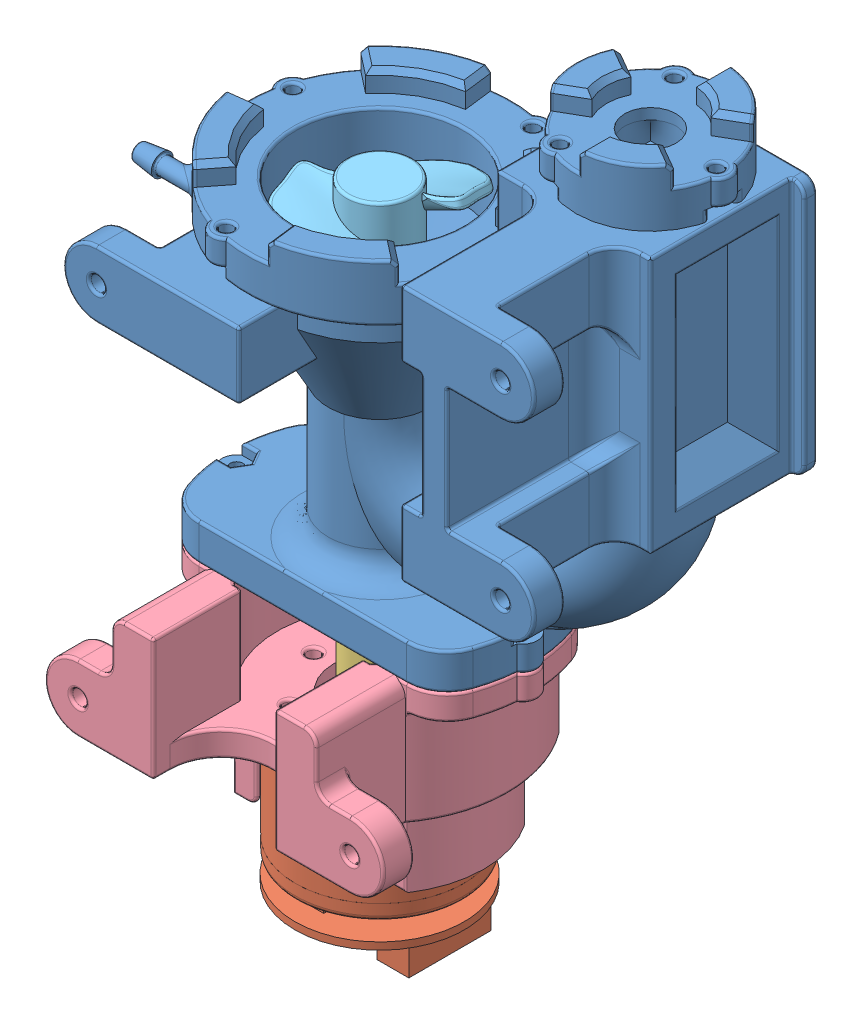
SolidWorks assembly Motor Connector Reference Assembly, configuration Default. Lengths in mm.
Overall size (95.4 152.33 58.74).
6 component instances, 6 part files, 18 mates.
Components (placement in the parent):
- Water Tunnel-1: Water Tunnel [Default] at origin size (93.6 95.16 58.74)
- 10kMotor-1: 10kMotor [Default] at (-41.4 -82.8 26.4) x (0 0 1) z (0 1 0) size (33 33 42.2)
- Shaft Cupling 2 to 3-1: Shaft Cupling 2 to 3 [Default] at (-41.4 -70 26.4) x (0 0 1) z (0 1 0) size (12 12 20)
- Motor Interface-1: Motor Interface [Default] at (0 -59 0) x (-1 0 0) z (0 -1 0) size (66 51.39 41.92)
- 5000rpm10cmHead-1: 5000rpm10cmHead [Default] at (-41.4 2.484 26.4) x (0 0 -1) z (-1 0 0) size (33.19 12.79 25.21)
- ImpellerShaft-1: ImpellerShaft [Default] at (-41.4 -70 26.4) x (0 0 1) z (0 1 0) size (3 3 74)
Mates (geometry in assembly coordinates):
- Coincident1: coordinate: point of Water Tunnel-1
- InPlace1: in place: plane of Water Tunnel-1 through (-41.4 -59 26.4) normal (0 -1 0); plane of Motor Interface-1 through (0 -59 0) normal (0 -1 0); moOrthogonalPlaneRef_w of Water Tunnel-1 through (-41.4 -59 26.4) normal (0 -1 0); plane of Motor Interface-1 through (0 -59 0) normal (0 0 -1); plane of Water Tunnel-1 through (-41.4 -59 26.4) normal (0 -1 0); plane of Motor Interface-1 through (0 -59 0) normal (-1 0 0); plane of Water Tunnel-1 through (-41.4 -59 26.4) normal (0 -1 0); unknown of Motor Interface-1
- Coincident2: coincident aligned: plane of Water Tunnel-1; plane of Motor Interface-1
- Coincident3: coincident aligned: moOrthogonalPlaneRef_w of Water Tunnel-1 through (0 -59 0) normal (0 0 -1); plane of Motor Interface-1 through (0 -59 0) normal (0 0 -1)
- Coincident4: coincident anti-aligned: moOrthogonalPlaneRef_w of Water Tunnel-1 through (0 -59 0) normal (1 0 0); plane of Motor Interface-1 through (0 -59 0) normal (-1 0 0)
- Concentric1: concentric aligned: cylinder of 10kMotor-1 through (-41.4 -114.8 26.4) axis (0 1 0) radius 1; cylinder of Shaft Cupling 2 to 3-1 through (-41.4 -80 26.4) axis (0 1 0) radius 1
- Distance5: distance = 1 mm anti-aligned: plane of 10kMotor-1 through (-41.4 -81 26.4) normal (0 1 0); plane of Shaft Cupling 2 to 3-1 through (-41.4 -80 26.4) normal (0 -1 0)
- Concentric2: concentric aligned: cylinder of 10kMotor-1 through (-41.4 -102.2 26.4) axis (0 1 0) radius 16.4; cylinder of Water Tunnel-1 through (-41.4 -59 26.4) axis (0 1 0) radius 5
- Distance3: distance = 1 mm anti-aligned: plane of Shaft Cupling 2 to 3-1 through (-41.4 -60 26.4) normal (0 1 0); plane of Water Tunnel-1 through (-41.4 -59 26.4) normal (0 -1 0)
- Parallel1: parallel anti-aligned: plane of Water Tunnel-1 through (0 0 0) normal (0 0 -1); plane of 10kMotor-1 through (-27.7 -115.5 34.4) normal (0 0 1)
- Coincident2: coincident aligned: plane of Water Tunnel-1 through (0 9 0) normal (0 1 0); plane of 5000rpm10cmHead-1 through (-41.4 9 26.4) normal (0 1 0)
- Concentric3: concentric anti-aligned: cylinder of Water Tunnel-1 through (-41.4 -4 26.4) axis (0 1 0) radius 16.4; cylinder of 5000rpm10cmHead-1 through (-41.4 13.2426 26.4) axis (0 -1 0) radius 1.5
- Parallel2: parallel anti-aligned: plane of Water Tunnel-1 through (0 0 58.6912) normal (0 0 1); plane of 5000rpm10cmHead-1 through (-41.4 2.484 26.4) normal (0 0 -1)
- InPlace2: in place: plane of ? through (-41.4 -67.5 26.4) normal (0 1 0); plane of ? through (0 -67.5 0) normal (0 1 0); plane of ? through (-41.4 -67.5 26.4) normal (0 1 0); plane of ? through (0 -67.5 0) normal (0 0 -1); plane of ? through (-41.4 -67.5 26.4) normal (0 1 0); plane of ? through (0 -67.5 0) normal (1 0 0); plane of ? through (-41.4 -70 26.4) normal (0 1 0); unknown of ?
- Coincident4: coincident aligned: plane of Shaft Cupling 2 to 3-1; plane of ImpellerShaft-1
- Coincident5: coincident aligned: moOrthogonalPlaneRef_w of Shaft Cupling 2 to 3-1; plane of ImpellerShaft-1 through (-41.4 -70 26.4) normal (1 0 0)
- Coincident6: coincident anti-aligned: moOrthogonalPlaneRef_w of Shaft Cupling 2 to 3-1; plane of ImpellerShaft-1 through (-41.4 -70 26.4) normal (0 0 1)
- Parallel3: parallel anti-aligned: plane of Shaft Cupling 2 to 3-1 through (-41.4 -70 26.4) normal (0 0 1); plane of Motor Interface-1 through (0 -64 11.4) normal (0 0 -1)
